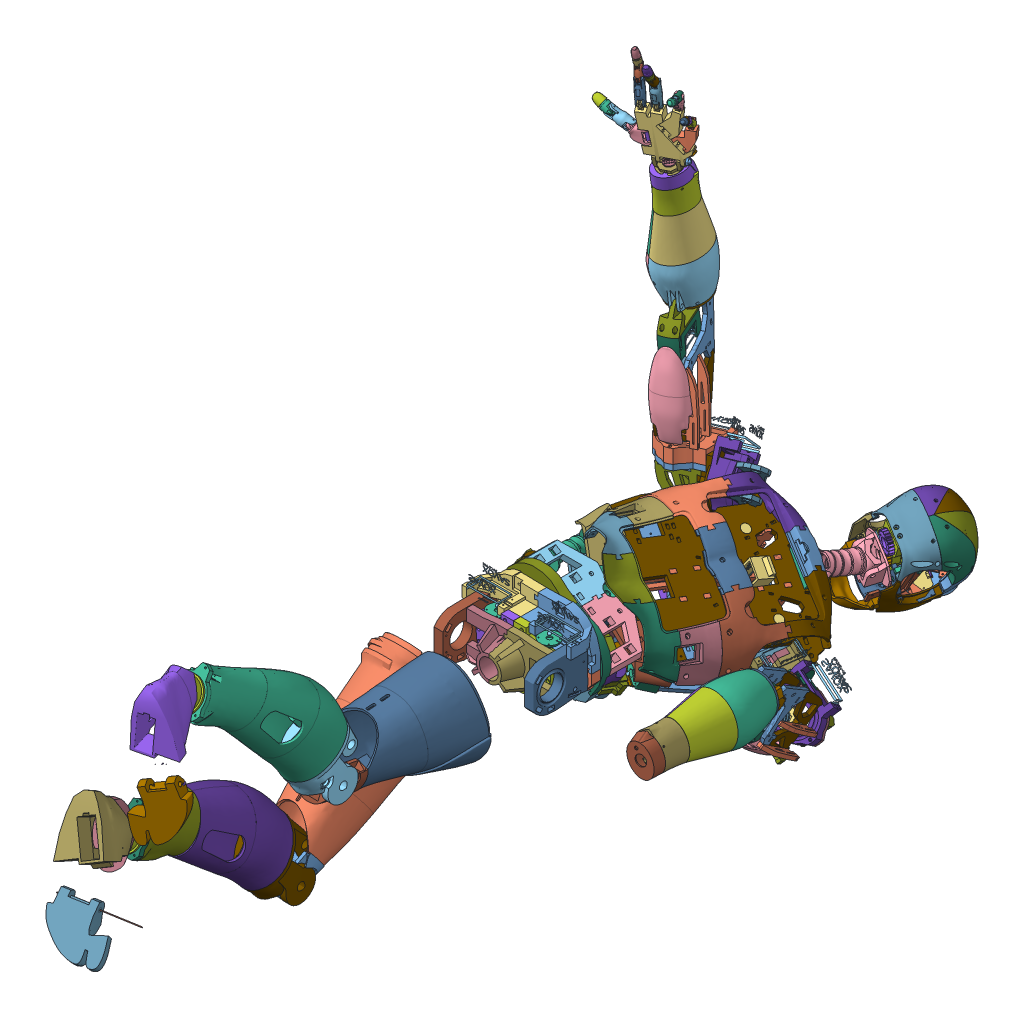
SolidWorks assembly inmoov, configuration 默认. Lengths in mm.
Overall size (1118.58 1250.99 1881.08).
271 component instances, 190 part files, 41 mates.
Components (placement in the parent):
- 盆骨-1: 盆骨 [默认] at (70.5927 39.7947 -15.7623) size (229.2 192.66 169.68)
  - 腹腔底10-1: 腹腔底10 [默认] at (-192.7214 -39.7004 -31.7756) size (122.01 95.66 63.55)
  - 腹腔底7-1: 腹腔底7 [默认] at (34.9288 -31.669 -31.7756) x (-1 0.000001 0) z (0 0.00001 1) size (144.05 113.37 90.99)
  - 腹腔底9-1: 腹腔底9 [默认] at (-192.7214 -39.7003 -31.7757) size (114.62 96.11 63.55)
  - 腹腔底8-1: 腹腔底8 [默认] at (34.9269 -31.6689 -31.7809) x (-1 -0.000002 0) z (0 0.000005 1) size (113.05 83.69 90.99)
  - 大舵机-1: 大舵机 [默认] at (-89.2868 14.2586 -3.7081) x (1 0 0) z (0 -0.000369 1) size (81.81 63.91 30.18)
  - 大舵机-3: 大舵机 [默认] at (-66.8639 10.2587 37.2872) x (-1 0 0) z (0 -0.000385 -1) size (81.81 63.91 30.18)
  - 腰部大螺栓-1: 腰部大螺栓 [默认] at (-193.5357 -116.8795 -27.4468) x (1 0 0) z (0 -0.000019 1) size (40.06 75.57 40.06)
  - 腰部大螺栓-2: 腰部大螺栓 [默认] at (-84.4909 -112.8794 -27.4312) x (1 0 0) z (0 -0.000013 1) size (40.06 75.57 40.06)
  - 盆骨1-1: 盆骨1 [默认] at (-156.4632 -100.0573 37.9672) x (0.00022 1 -0.000011) z (0 -0.000011 -1) size (127.7 105.68 15.11)
  - 盆骨2-1: 盆骨2 [默认] at (-156.2886 -100.4214 37.9672) x (-0.004429 0.99999 -0.000011) z (-0.000001 -0.000011 -1) size (127.7 78.47 15.11)
  - 腰部脊柱-1: 腰部脊柱 [默认] at (96.5025 -51.1472 22.3076) x (-0.920661 -0.390363 0.000004) z (0.000001 -0.000011 -1) size (94.05 93.78 91.39)
  - 盆腔右-1: 盆腔右 [默认] at (7.5496 -34.1365 36.3698) x (-0.003482 -0.003095 0.999989) z (0.999994 -0.000011 0.003482) size (127.1 98.38 18.86)
  - 盆腔大腿连接-1: 盆腔大腿连接 [默认] at (-164.2868 -34.1439 37.2078) x (-0.003562 0.003181 -0.999989) z (-0.999994 -0.000011 0.003562) size (127.1 98.38 18.86)
  - 盆骨4-1: 盆骨4 [默认] at (7.7497 18.3053 37.9656) x (-0.999967 -0.00818 0) z (0 0.000013 1) size (113.34 100.96 52.24)
  - 盆骨3-1: 盆骨3 [默认] at (8.5006 17.6463 37.9656) x (-1 -0.000493 0) z (0 0.000013 1) size (86.16 100.96 52.24)
- 腹腔底-1: 腹腔底 [默认] at (-4.5335 -58.4913 -79.9024) x (-0.842788 0.538245 -0.000007) z (0.000001 -0.000012 -1) size (236.98 173.63 160.06)
  - 腹腔底1-1: 腹腔底1 [默认] at (-115.9898 -31.5228 -86.4581) size (118.38 83.69 62.88)
  - 腹腔底3-1: 腹腔底3 [默认] at (-115.9897 -31.5228 -86.4581) x (1 0.000001 0) z (0 0 1) size (120.65 97.33 18.16)
  - 腹腔底4-1: 腹腔底4 [默认] at (-116.1614 -30.8776 -86.4608) x (0.999991 -0.004202 -0.000001) z (0.000001 0 1) size (144.03 121.61 18.16)
  - 腹腔底5-1: 腹腔底5 [默认] at (-115.9897 -31.5229 -86.458) x (1 0.000001 0) z (0 0.000001 1) size (61.43 24.96 50.27)
  - 腹腔底6-1: 腹腔底6 [默认] at (-116.1614 -30.8776 -86.4607) x (0.999991 -0.004202 -0.000001) z (0.000001 0 1) size (61.43 24.96 50.27)
  - 腹腔底2-1: 腹腔底2 [默认] at (-116.1614 -30.8774 -86.458) x (0.999991 -0.004202 -0.000001) z (0.000001 0 1) size (125.86 83.69 62.88)
  - 腰部脊柱2-1: 腰部脊柱2 [默认] at (-46.5918 207.4732 -86.4608) x (-0.004521 -0.99999 0) z (0 0 1) size (79.07 79.07 18.22)
  - 腹腔中前-1: 腹腔中前 [默认] at (-115.9166 -30.878 -86.4712) x (0.999991 -0.004202 -0.000001) z (0.000001 -0.000001 1) size (118.93 16.66 147.82)
  - 腹腔中背1-1: 腹腔中背1 [默认] at (-115.9899 -31.5227 -86.4302) x (1 0.000001 -0.000002) z (0.000002 -0.000001 1) size (113.55 25.26 111.94)
  - 腹腔中背2-1: 腹腔中背2 [默认] at (-116.1614 -30.8776 -86.4328) x (0.999991 -0.004202 -0.000001) z (0.000001 0 1) size (113.52 25.26 111.94)
  - 腹腔中-1: 腹腔中 [默认] at (-116.0394 -30.7589 -86.2911) x (0.999991 -0.004203 0) z (0 -0.000001 1) size (88.8 54.93 88.79)
  - 腹腔中2-1: 腹腔中2 [默认] at (-116.0669 -30.7588 -86.2536) x (0.999991 -0.004202 0) z (0 -0.000001 1) size (88.8 48.64 88.8)
  - 装饰-腹腔-1: 装饰-腹腔 [默认] at (-33.2725 -10.645 128.5221) x (0.000684 -0.000002 -1) z (-0.004202 -0.999991 -0.000001) size (73.69 73.49 13.68)
  - 装饰-腹腔-2: 装饰-腹腔 [默认] at (108.4671 -11.2406 -13.0249) x (-0.000684 0.000002 1) z (-0.004202 -0.999991 -0.000001) size (73.69 73.49 13.68)
  - 装饰-腹腔-3: 装饰-腹腔 [默认] at (108.3702 -11.2402 128.6191) x (-0.999991 0.004202 -0.000684) z (-0.004202 -0.999991 -0.000001) size (73.69 73.49 13.68)
  - 装饰-腹腔-4: 装饰-腹腔 [默认] at (-33.1756 -10.6453 -13.1219) x (0.999991 -0.004202 0.000684) z (-0.004202 -0.999991 -0.000001) size (73.69 73.49 13.68)
- 腹腔上-1: 腹腔上 [默认] at (48.5045 -53.3308 -158.6881) x (-0.793643 0.502129 -0.343506) z (0.290273 -0.18368 -0.93915) size (307.58 77.32 113.84)
  - 腹腔前1-1: 腹腔前1 [默认] at (-79.3802 -63.8968 -192.1693) size (103 23.38 76.42)
  - 腹腔后1-1: 腹腔后1 [默认] at (227.4254 159.402 -192.6182) x (-0.999998 -0.000036 0.002224) z (0.002224 -0.000001 0.999998) size (96.82 10.08 80.86)
  - 腹腔后2-1: 腹腔后2 [默认] at (-79.8769 -63.9893 -191.9254) x (0.999997 0.000073 -0.002314) z (0.002314 -0.000001 0.999997) size (112.71 23.37 76.42)
  - 腹腔后3-1: 腹腔后3 [默认] at (-80.266 -63.9781 -191.4841) x (0.99999 0 -0.004449) z (0.004449 -0.000001 0.99999) size (112.71 23.37 76.42)
  - 腹腔后1-2: 腹腔后1 [默认] at (-79.8184 -130.9308 -191.935) x (0.999998 0.000036 -0.002225) z (0.002225 0 0.999998) size (96.82 10.08 80.86)
  - 腹腔中3-1: 腹腔中3 [默认] at (-80.0009 -63.5291 -193.4037) x (0.999965 -0.004935 0.006744) z (-0.006745 -0.000033 0.999977) size (86.15 66.75 71.31)
  - 腹腔前2-1: 腹腔前2 [默认] at (-79.759 -63.9636 -191.9533) x (0.999998 0.000073 -0.002134) z (0.002134 0 0.999998) size (103 23.38 76.42)
  - 腰肌螺母-1: 腰肌螺母 [默认] at (171.7646 -14.2155 -47.3665) x (0.997648 0.000036 0.068548) z (-0.068548 -0.000004 0.997648) size (50.56 57 34.3)
  - 腰肌螺母-3: 腰肌螺母 [默认] at (-19.0221 42.7776 -45.2497) x (-0.999985 -0.000036 -0.005434) z (-0.005434 -0.000002 0.999985) size (50.56 57 34.3)
- 腰部-1: 腰部 [默认] at (43.4407 -39.2735 -108.6148) x (-0.7938 0.506957 -0.335971) z (0.283148 -0.180841 -0.941872) size (88.76 53.21 141.98)
  - 腰部舵机安装盒-1: 腰部舵机安装盒 [默认] at (-60.724 -20.5722 -23.2224) size (87.93 52.56 34.36)
  - 大舵机-1: 大舵机 [默认] at (-100.7443 -15.1822 39.809) x (1 0 -0.000002) z (0 1 0.000383) size (81.81 63.91 30.18)
  - 舵机盘-1: 舵机盘 [默认] at (-61.0228 -14.6756 36.5262) x (0.992401 0.000027 -0.123044) z (0.123044 -0.000435 0.992401) size (40.31 40 12.26)
  - 腰部大螺栓-1: 腰部大螺栓 [默认] at (-108.8185 -9.5775 169.4468) x (0.909531 -0.415637 -0.000003) z (0.415637 0.909531 0.000025) size (40.06 75.57 40.06)
- 腰部-2: 腰部 [默认] at (-62.5662 40.207 -95.5581) x (0.844485 -0.53435 0.036267) z (0.030644 -0.019398 -0.999342) size (88.76 53.21 141.98)
  - 腰部舵机安装盒-1: 腰部舵机安装盒 [默认] at (-60.724 -20.5722 -23.2224) size (87.93 52.56 34.36)
  - 大舵机-1: 大舵机 [默认] at (-100.7443 -15.1822 39.809) x (1 0 -0.000002) z (0 1 0.000383) size (81.81 63.91 30.18)
  - 舵机盘-1: 舵机盘 [默认] at (-61.0228 -14.6756 36.5262) x (0.992401 0.000027 -0.123044) z (0.123044 -0.000435 0.992401) size (40.31 40 12.26)
  - 腰部大螺栓-1: 腰部大螺栓 [默认] at (-108.8185 -9.5775 169.4468) x (0.909531 -0.415637 -0.000003) z (0.415637 0.909531 0.000025) size (40.06 75.57 40.06)
- 身子板-1: 身子板 [默认] at (-659.1415 377.3457 523.4472) x (-0.069913 0.797457 -0.599312) z (-0.784162 -0.415288 -0.461114) size (516.48 525.32 527.33)
  - 后背板-1: 后背板 [默认] at (143.3492 1191.9158 -17.9372) x (-0.6608 0.486586 -0.57147) z (0.636508 -0.040187 -0.770222) size (310.71 330.4 10)
  - 胸前板-1: 胸前板 [默认] at (61.9607 1209.7037 0.4805) x (-0.6608 0.486586 -0.57147) z (0.636508 -0.040187 -0.770222) size (310.06 296.42 10)
  - 脊柱1-1: 脊柱1 [默认] at (34.0384 1054.7167 -14.5078) x (0.6608 -0.486586 0.57147) z (0.397745 0.872708 0.28316) size (54.6 76.71 282.55)
  - 脊柱1-2: 脊柱1 [默认] at (65.4264 1031.6039 12.6371) x (0.6608 -0.486586 0.57147) z (0.397745 0.872708 0.28316) size (54.6 76.71 282.55)
  - 胸肌3-1: 胸肌3 [默认] at (252.0953 1308.157 52.803) x (0.61608 -0.574219 0.539183) z (-0.463673 -0.81773 -0.341066) size (37.4 76.95 25.87)
  - 胸肌3-2: 胸肌3 [默认] at (117.556 1377.4336 -61.9943) x (0.749033 -0.205605 0.629822) z (-0.1834 -0.977826 -0.101096) size (37.4 76.95 25.87)
  - 装饰-腹腔-上-1: 装饰-腹腔-上 [默认] at (-153.4195 944.3871 -111.8547) x (0.661803 -0.484378 0.572185) z (0.396073 0.873935 0.281715) size (98.85 49.72 33.76)
  - 装饰-腹腔-上2-1: 装饰-腹腔-上2 [默认] at (85.1244 1050.2994 15.2678) x (0.660957 -0.486242 0.571581) z (-0.397485 -0.8729 -0.282935) size (98.85 49.72 33.76)
  - 装饰-胸腔1-1: 装饰-胸腔1 [默认] at (-74.1529 1143.352 -37.1333) x (0.6608 -0.486586 0.57147) z (0.397745 0.872708 0.28316) size (109.48 65.08 34.36)
  - 装饰-胸腔2-1: 装饰-胸腔2 [默认] at (-74.6569 1143.2216 -36.3801) x (0.6608 -0.486586 0.57147) z (0.397745 0.872708 0.28316) size (69.28 69.05 67.19)
  - 装饰-胸腔3-1: 装饰-胸腔3 [默认] at (-74.46 1143.7266 -36.7278) x (0.6608 -0.486586 0.57147) z (0.397745 0.872708 0.28316) size (109.15 65.08 34.37)
  - 装饰-胸腔4-1: 装饰-胸腔4 [默认] at (-74.0615 1142.7469 -36.9122) x (0.660896 -0.486866 0.57112) z (0.397947 0.872559 0.283335) size (119.01 63.05 121.18)
  - 装饰-胸腔5-1: 装饰-胸腔5 [默认] at (-74.3693 1142.9367 -36.8164) x (0.660864 -0.485825 0.572042) z (0.397182 0.873122 0.282673) size (119.01 63.06 121.15)
  - 装饰-胸腔6-1: 装饰-胸腔6 [默认] at (44.1853 1289.4703 15.9146) x (0.661053 -0.486028 0.571651) z (0.397323 0.873019 0.282795) size (117.32 26.45 49.76)
  - 装饰-胸腔7-1: 装饰-胸腔7 [默认] at (44.3553 1289.8426 16.0358) x (0.659604 -0.489202 0.570618) z (0.399726 0.871244 0.284874) size (117.42 26.45 49.76)
  - 装饰-胸腔-搞什么啊这个也要分开两个明明一个就可以-1: 装饰-胸腔-搞什么啊这个也要分开两个明明一个就可以 [默认] at (37.1283 1215.9714 45.2793) x (0.6608 -0.486586 0.57147) z (0.397745 0.872708 0.28316) size (138.82 53.92 70.62)
  - 装饰-腹腔-上3-1: 装饰-腹腔-上3 [默认] at (-52.0677 1129.5819 -35.7586) x (0.6608 -0.486586 0.57147) z (0.397745 0.872708 0.28316) size (131.99 51.42 32.36)
  - 装饰-腹腔-上4-1: 装饰-腹腔-上4 [默认] at (-51.2643 1128.8117 -35.0374) x (0.6608 -0.486586 0.57147) z (0.397745 0.872708 0.28316) size (131.99 51.42 32.36)
  - 装饰-背部-1: 装饰-背部 [默认] at (556.6771 1211.3347 228.4405) x (0.653769 -0.401724 0.641252) z (0.325737 -0.615491 -0.717681) size (351.18 364.48 345.06)
    - 装饰-背部2-1: 装饰-背部2 [默认] at (-578.9545 274.381 92.1313) x (0.989065 0.068101 0.130814) z (0.134185 -0.783586 -0.606619) size (111.18 27.71 50.53)
    - 装饰-背部3-1: 装饰-背部3 [默认] at (-579.0285 274.2163 91.9579) x (0.988774 0.069516 0.132264) z (0.13619 -0.783443 -0.606358) size (118.1 95.29 111.5)
    - 装饰-背部4-1: 装饰-背部4 [默认] at (-583.8515 325.981 132.3484) x (0.988455 0.07552 0.131351) z (0.140337 -0.783133 -0.605812) size (70.93 77.01 90.21)
    - 装饰-背部5-1: 装饰-背部5 [默认] at (-581.9356 326.1989 132.2577) x (0.98844 0.071421 0.133738) z (0.138594 -0.783263 -0.606045) size (70.91 77.12 90.21)
    - 装饰-背部6-1: 装饰-背部6 [默认] at (-573.266 248.1563 194.7745) x (0.988455 0.075515 0.131352) z (-0.140333 0.783133 0.605813) size (111.34 97.12 112.81)
    - 装饰-背部7-1: 装饰-背部7 [默认] at (-571.5995 248.3153 194.9496) x (0.988701 0.074142 0.13028) z (-0.138594 0.783263 0.606045) size (111.34 97.12 112.81)
    - 装饰-背部8-2: 装饰-背部8 [默认] at (-571.9454 247.7082 194.4628) x (0.987776 0.079245 0.134236) z (-0.14504 0.782763 0.605182) size (84.93 29.99 71.45)
    - 装饰-背部-上-1: 装饰-背部-上 [默认] at (-541.2593 199.9763 28.2233) x (0.988704 0.06993 0.132565) z (0.136627 -0.784148 -0.605347) size (112.37 87.9 117.46)
    - 装饰-背部-上2-1: 装饰-背部-上2 [默认] at (-541.292 199.909 28.179) x (0.988658 0.070179 0.132776) z (0.136952 -0.784125 -0.605303) size (112.42 86.19 116.36)
    - 装饰-背部-上3-2: 装饰-背部-上3 [默认] at (-541.6661 199.5094 29.6724) x (0.98915 0.071334 0.128425) z (0.135493 -0.780835 -0.609868) size (76.75 23.59 35.23)
    - 装饰-背部9-1: 装饰-背部9 [默认] at (-578.8974 274.377 92.0652) x (0.989048 0.067927 0.131035) z (0.134185 -0.783586 -0.606619) size (118.1 95.29 111.5)
- 颈部舵机包裹盒-1: 颈部舵机包裹盒 [默认] at (66.463 -67.2427 -357.0875) x (-0.794313 0.502684 -0.341139) z (0.227875 -0.274003 -0.934342) size (53.5 87.93 30.73)
- 大舵机-1: 大舵机 [默认] at (21.2826 -92.8743 -428.0501) x (0.563153 0.819896 -0.103099) z (0.794399 -0.502788 0.340784) size (81.81 63.91 30.18)
- 颈椎-1: 颈椎 [默认] at (327.5718 -830.9296 572.5602) x (-0.806641 0.510346 -0.298123) z (0.259011 -0.148159 -0.954443) size (60.66 53.48 115.35)
- 颈部连接-1: 颈部连接 [默认] at (100.7339 -79.9016 -435.0873) x (-0.794355 0.502623 -0.34113) z (0.288264 -0.182411 -0.940016) size (54.59 64.81 34.68)
- 颈部连接2-1: 颈部连接2 [默认] at (100.5898 -79.8584 -435.1883) x (-0.7943 0.502587 -0.341312) z (0.288418 -0.182507 -0.93995) size (69.42 17.54 31.49)
- 头-1: 头 [默认] at (159.0523 55.7112 -671.473) x (-0.81491 0.49549 -0.300686) z (0.388055 0.081094 -0.918062) size (147.84 221.42 240.31)
  - 支架-2: 支架 [默认] at (-124.447 -159.0127 -70.7992) size (53.91 91.64 57.56)
  - 颈椎齿轮1-2: 颈椎齿轮1 [默认] at (-81.2129 -98.5858 -79.9856) size (42.66 42.67 32.83)
  - 颈椎齿轮2-2: 颈椎齿轮2 [默认] at (-82.3614 -57.8278 -79.9768) x (0.087374 -0.996176 0) z (0 0 1) size (42.66 42.66 44.97)
  - 脸部右支架-2: 脸部右支架 [默认] at (-124.6512 -158.9164 -70.9912) x (0.999993 -0.00385 0) z (0 0 1) size (50.18 81.65 18.67)
  - 下颚右支架-2: 下颚右支架 [默认] at (-105.7528 -137.0128 -114.8083) x (0.999987 -0.003839 0.003287) z (-0.003661 -0.101881 0.99479) size (8.26 106.97 83.58)
  - 大舵机-1: 大舵机 [默认] at (-79.6637 -141.6142 -32.115) x (0 0.999997 0.002621) z (0.999996 -0.000007 0.002719) size (81.81 63.91 30.18)
  - 舵机支架-2: 舵机支架 [默认] at (-124.9768 -158.8555 -71.2485) x (0.999995 -0.000008 0.003099) z (-0.003099 -0.002621 0.999992) size (64.63 107.35 76.67)
  - 迷你舵机-2: 迷你舵机 [默认] at (-48.2513 -135.944 28.1702) x (-0.999986 -0.004998 0.001659) z (-0.000305 -0.259577 -0.965722) size (32.82 12.3 30.6)
  - 后脑勺-2: 后脑勺 [默认] at (-472.2134 -287.0548 -1807.4761) x (0.999892 0.014512 -0.002292) z (0.001793 0.034306 0.99941) size (136.35 70.29 65.6)
  - 后脑右-2: 后脑右 [默认] at (-134.4625 -95.0757 -21.5694) x (0.99996 0.004746 -0.007645) z (0.007474 0.03506 0.999357) size (72.75 112.74 72.41)
  - 后脑右上-2: 后脑右上 [默认] at (-470.5392 -285.4493 -1807.7537) x (0.999944 0.010512 -0.000771) z (0.000404 0.034862 0.999392) size (54.09 115.71 76.28)
  - 后脑左-2: 后脑左 [默认] at (-133.0899 -96.0354 -22.0012) x (0.999891 0.014487 -0.002996) z (0.002487 0.035016 0.999384) size (72.75 112.69 72.41)
  - 后脑左上-2: 后脑左上 [默认] at (-485.3133 -292.4826 -1803.1863) x (0.999906 0.010204 -0.009158) z (0.008757 0.038668 0.999214) size (66.14 115.71 76.29)
  - 前额右-1: 前额右 [默认] at (-485.0704 -271.1759 -1806.139) x (0.999871 0.013496 -0.008737) z (0.008381 0.026215 0.999621) size (72.11 94.93 64.78)
  - 前额右上-1: 前额右上 [默认] at (-457.4772 -289.9568 -1810.8211) x (0.999517 0.030818 0.004033) z (-0.005025 0.03218 0.999469) size (85.15 107.55 75.34)
  - 前额左-1: 前额左 [默认] at (-473.2004 -218.3333 -1813.179) x (0.999982 0.005763 -0.001907) z (0.001915 -0.001235 0.999997) size (91.46 102.46 64.78)
  - 前额左上-1: 前额左上 [默认] at (-467.29 -207.0531 -1815.3492) x (0.999805 -0.019571 0.002504) z (-0.002528 -0.001167 0.999996) size (80.92 107.55 80.15)
  - 脸部支架-1: 脸部支架 [默认] at (-124.4772 -159.0849 -70.9912) x (1 0 0) z (0 0 1) size (50.3 81.55 19.17)
  - 下颚传动右-1: 下颚传动右 [默认] at (-124.473 -158.7731 -70.8425) x (0.999987 -0.003839 0.003287) z (-0.003274 0.003227 0.999989) size (17.04 36.62 42.69)
  - 下颚传动左-1: 下颚传动左 [默认] at (-124.6359 -159.1135 -69.5647) x (0.999554 0.000509 -0.029855) z (0.02986 -0.017025 0.999409) size (17.04 36.62 42.69)
  - 下颚支架2-1: 下颚支架2 [默认] at (-110.2934 -133.1949 -115.5804) x (0.999554 0.000509 -0.029855) z (0.029561 -0.157888 0.987015) size (8.26 106.97 83.58)
  - 下颚-1: 下颚 [默认] at (-522.7989 64.0778 -1802.2262) x (0.999625 0.002745 -0.027234) z (0.027326 -0.157888 0.987079) size (113.02 62.78 57.99)
  - 上颚-1: 上颚 [默认] at (-472.0966 -231.4046 -1812.4343) x (0.999982 0.005763 -0.001859) z (0.001823 0.006208 0.999979) size (141.83 76.87 99.46)
  - 脸-1: 脸 [默认] at (-124.4869 -198.7826 -68.0514) x (0.999982 0.005763 -0.001864) z (0.00182 0.007618 0.999969) size (130.55 56.05 65.23)
  - 耳朵-1: 耳朵 [默认] at (-134.5341 -125.1811 -74.3435) x (0.999786 -0.009234 0.01852) z (-0.01668 0.170193 0.98527) size (16.1 91.01 91.01)
  - 耳根-1: 耳根 [默认] at (49.6286 -51.4238 -103.8814) x (0.999982 0.005763 -0.001864) z (0.00182 0.007618 0.999969) size (22.04 103.89 112.83)
  - 眼睛支架-1: 眼睛支架 [默认] at (-108.8481 -200.0988 -91.2528) x (0.999986 0.005204 -0.000894) z (-0.000487 0.259573 0.965723) size (65.05 33.31 75.11)
  - 眼球-1: 眼球 [默认] at (-37.7048 -168.4489 -19.8199) x (0.742559 0.129649 -0.657113) z (0.55836 0.422027 0.714232) size (36.68 12.46 36.68)
  - 眼球板-1: 眼球板 [默认] at (-41.6405 -162.3342 -45.3078) x (0.929364 0.356416 -0.096182) z (0.000385 0.259603 0.965715) size (33.8 15.18 44.6)
  - 眼球板附加-1: 眼球板附加 [默认] at (-90.8952 -224.7754 -84.1839) x (0.929364 0.356438 -0.0961) z (0.000313 0.259557 0.965728) size (30.53 13.48 33.7)
  - 眼球左右传动板-1: 眼球左右传动板 [默认] at (-13.1585 -143.7871 100.851) x (-0.997305 -0.070778 0.019339) z (-0.000305 -0.259576 -0.965723) size (35.43 8.85 2.99)
  - 迷你舵机-3: 迷你舵机 [默认] at (-37.698 -157.934 -40.8747) x (-0.006048 0.965705 -0.259571) z (-0.999982 -0.005762 0.001864) size (32.82 12.3 30.6)
  - 下颚螺母连接块-1: 下颚螺母连接块 [默认] at (-102.7393 -60.0107 -39.1407) x (0.999554 0.000509 -0.029855) z (0.029271 0.180858 0.983074) size (86.95 16.37 12.1)
  - 右耳根-1: 右耳根 [默认] at (-134.1706 -208.8052 -146.4024) x (0.999982 0.005763 -0.001864) z (0.00182 0.007618 0.999969) size (17.42 103.79 112.96)
  - 鼻骨-1: 鼻骨 [默认] at (-124.5584 -198.8505 -68.1492) x (0.999982 0.005763 -0.001864) z (0.00182 0.007616 0.999969) size (21 31.57 49.5)
  - 耳朵-2: 耳朵 [默认] at (10.2094 -58.2202 -97.4824) x (-0.999622 -0.016404 0.022043) z (0.013501 0.405482 0.914003) size (16.1 91.01 91.01)
  - 眼球板-右-1: 眼球板-右 [默认] at (-104.0961 -165.6703 -44.3805) x (0.9254 0.365928 -0.098651) z (0.000306 0.259576 0.965723) size (33.8 15.22 44.6)
  - 眼球板附加-右-1: 眼球板附加-右 [默认] at (-94.3263 -205.4862 -89.3547) x (0.9254 0.365928 -0.09865) z (0.000313 0.259557 0.965728) size (30.53 13.48 33.7)
  - 眼球-2: 眼球 [默认] at (-93.486 -163.662 0.7412) x (-0.309518 -0.367105 -0.877173) z (0.872458 0.257233 -0.415509) size (36.68 12.46 36.68)
  - 眼球左右传动板-2: 眼球左右传动板 [默认] at (-121.0355 -192.8146 -92.7775) x (0.99458 -0.100492 0.026697) z (0.000305 0.259577 0.965722) size (35.43 8.85 2.99)
- 颈椎上-1: 颈椎上 [默认] at (-279.4452 -552.5793 1065.328) x (-0.806305 0.512366 -0.295558) z (0.388055 0.081094 -0.918062) size (92.29 80.59 33.71)
- 颈部肌肉螺栓-1: 颈部肌肉螺栓 [默认] at (39.8383 -63.0159 -361.6888) x (-0.193286 0.927762 -0.319216) z (0.227872 -0.274007 -0.934342) size (39.72 39.72 100.52)
- 颈部肌肉-1: 颈部肌肉 [默认] at (45.7079 -68.3009 -373.5197) x (-0.274536 0.902575 -0.331646) z (0.227871 -0.274007 -0.934342) size (28.08 28.58 122.79)
- 右脚-1: 右脚 [默认] at (-9.6404 -547.6759 575.1252) x (-0.687566 -0.511254 -0.515629) z (0.723091 -0.546902 -0.421945) size (820.43 699.67 726.99)
  - 右小腿-1: 右小腿 [默认] at (-400.1104 -176.0875 -338.5039) x (0.826596 -0.548948 -0.124075) z (-0.193597 -0.484354 0.853183) size (371.31 442.39 332.73)
    - 膝盖右下-1: 膝盖右下 [默认] at (-523.7529 501.294 -106.0649) x (0.676216 -0.047439 -0.735174) z (0.529558 0.725052 0.440304) size (103.93 135.07 96.53)
    - 右小腿-1: 右小腿 [默认] at (-1509.5207 407.2534 356.5703) x (0.676217 -0.047438 -0.735174) z (0.427539 0.837953 0.339183) size (125.4 159.22 355.37)
  - 脚踝-1: 脚踝 [默认] at (-626.971 399.431 -514.5499) x (-0.479837 0.817786 0.317778) z (-0.730035 -0.171261 -0.661602) size (66.72 66.73 45.96)
  - 右脚-1: 右脚 [默认] at (-1815.1824 1208.5317 561.4844) x (0.460628 -0.248169 -0.852194) z (0.711788 0.676872 0.187623) size (110.05 224.47 118.54)
  - 右脚趾-1: 右脚趾 [默认] at (316.2614 -486.3972 -1339.3575) x (-0.465224 0.252235 0.848495) z (0.70204 0.688985 0.180107) size (97.91 137.78 40.59)
  - 大腿右-1: 大腿右 [默认] at (-23.3857 -51.9681 0) size (470.68 508.98 446.5)
    - 大腿右侧-已翻转-1: 大腿右侧-已翻转 [默认] at (246.4325 -358.6742 385.4816) x (0.689353 -0.063677 -0.721621) z (0.569669 0.66301 0.485691) size (162.86 209.38 464.67)
    - 膝盖右上-1: 膝盖右上 [默认] at (-108.0099 340.3112 -728.0834) x (0.676216 -0.047439 -0.735174) z (-0.50532 -0.756033 -0.416011) size (109 86.01 77.55)
- 右手-1: 右手 [默认] at (-303.0662 524.5668 645.1342) x (0.944725 -0.121151 0.304657) z (0.242681 0.883202 -0.401322) size (537.65 583.01 323.75)
  - 右肩内-1: 右肩内 [默认] at (-554.4913 207.3714 -41.3596) x (-0.259119 0.270063 0.927321) z (-0.767636 0.525104 -0.367424) size (165.73 145.33 179.96)
    - 右手11-1: 右手11 [默认] at (-66.7029 2791.7652 -1676.8682) x (0.419842 -0.819664 0.389722) z (0.645927 0.571499 0.50613) size (37.79 102.6 113.4)
    - 右手2-1: 右手2 [默认] at (148.1443 1489.8573 -466.1757) x (0.419847 -0.819659 0.389727) z (0.644936 0.571566 0.507316) size (15.58 90.74 103.51)
    - 肩胛骨-1: 肩胛骨 [默认] at (64.3449 1261.6061 -25.7326) x (-0.419847 0.819659 -0.389727) z (-0.638581 0.038354 0.768598) size (53.97 102.32 7.5)
    - 肩胛骨-2: 肩胛骨 [默认] at (93.0578 1259.8856 -60.283) x (-0.419847 0.819659 -0.389727) z (-0.638581 0.038354 0.768598) size (53.97 102.32 7.5)
    - 大舵机-1: 大舵机 [默认] at (37.9422 1228.7537 -119.7914) x (0.645835 0.571505 0.506241) z (-0.420179 0.819685 -0.389315) size (81.81 63.91 30.18)
  - 右肩-1: 右肩 [默认] at origin size (162.66 157.92 218.84)
    - 右手肩部肩胛传动-1: 右手肩部肩胛传动 [默认] at (1087.3872 2772.2295 3074.4342) x (-0.888426 -0.343703 0.30425) z (-0.433363 0.846544 -0.309127) size (30.18 101.64 100.56)
    - 肩部直角件-1: 肩部直角件 [默认] at (282.9051 1259.6079 -33.3815) x (0.88669 0.346881 -0.305702) z (-0.436818 0.8452 -0.30794) size (77.13 53.27 74.94)
    - 肩部直角件-2: 肩部直角件 [默认] at (276.0584 1241.2276 -74.0957) x (0.88669 0.346881 -0.305702) z (-0.436818 0.8452 -0.30794) size (77.13 53.27 74.94)
    - 右手2-1: 右手2 [默认] at (452.6345 1141.8665 366.7625) x (-0.437587 0.844899 -0.307674) z (0.886311 0.347615 -0.305969) size (15.58 90.74 103.51)
    - 右手4-1: 右手4 [默认] at (2509.158 5052.0987 7340.4223) x (-0.88622 -0.347387 0.30649) z (-0.437571 0.844956 -0.307539) size (110.5 102.59 37.78)
    - 大舵机-1: 大舵机 [默认] at (234.6575 1242.8525 -4.5609) x (0.88622 0.347387 -0.30649) z (0.437514 -0.84511 0.307197) size (81.81 63.91 30.18)
  - 手大臂-1: 手大臂 [默认] at (281.4226 98.1435 194.7173) x (0.5894 0.372248 0.716965) z (-0.807537 0.295872 0.510239) size (168.57 259.68 213.5)
    - 肩部大臂传动-1: 肩部大臂传动 [默认] at (387.2336 923.2205 71.7955) x (-0.731537 0.195249 -0.653246) z (-0.163767 0.879749 0.446343) size (92.57 93.45 30.17)
    - 左肩7-1: 左肩7 [默认] at (272.9463 951.3318 1.1554) x (0.745885 -0.299351 0.595017) z (-0.661867 -0.433357 0.611665) size (120.84 98.18 7.5)
    - 左肩7-2: 左肩7 [默认] at (242.8694 931.6386 28.9516) x (0.745885 -0.299351 0.595017) z (-0.661867 -0.433357 0.611665) size (120.84 98.18 7.5)
    - 左肩8-1: 左肩8 [默认] at (243.1543 931.2846 29.009) x (0.745697 -0.297235 0.596312) z (-0.661867 -0.433357 0.611665) size (117.33 120.91 7.5)
    - 左肩8-2: 左肩8 [默认] at (273.2313 950.9777 1.2129) x (0.745697 -0.297235 0.596312) z (-0.661867 -0.433357 0.611665) size (117.33 120.91 7.5)
    - 左手1-1: 左手1 [默认] at (376.8563 964.0188 -11.4035) x (-0.661867 -0.433359 0.611664) z (-0.154337 0.87726 0.454527) size (26.4 52.78 131.72)
    - 左手1-2: 左手1 [默认] at (239.2225 868.3069 126.4972) x (0.661867 0.433355 -0.611666) z (-0.1551 0.877477 0.453849) size (26.4 52.78 131.72)
    - 二头肌3-1: 二头肌3 [默认] at (204.2298 1244.5751 220.1542) x (0.662738 0.432715 -0.611175) z (0.095007 -0.858141 -0.504547) size (52.98 38.41 29.61)
    - 装饰-手-1: 装饰-手 [默认] at (273.6933 1134.3266 115.4714) x (-0.661867 -0.433357 0.611665) z (0.164084 -0.879931 -0.445868) size (72.28 34.51 167.42)
  - 右手小臂-1: 右手小臂 [默认] at (460.3119 1000.0381 4.7231) x (-0.891849 -0.449213 0.053033) z (0.413408 -0.857063 -0.30747) size (104.14 106.75 306.73)
    - 手小臂4-1: 手小臂4 [默认] at (-35.3772 -52.064 -52.8214) size (92.61 92.23 105.64)
    - 手小臂1-1: 手小臂1 [默认] at (-46.9087 -66.5848 -52.8216) x (1 -0.000001 0.000002) z (-0.000002 -0.000002 1) size (95.98 93.78 105.56)
    - 手小臂2-1: 手小臂2 [默认] at (-46.9299 -66.5664 -52.8214) x (1 0 0) z (0 0 1) size (89.17 83.71 97.5)
    - 手小臂3-1: 手小臂3 [默认] at (-35.3833 -52.0586 -52.8214) x (1 0 0) z (0 0 1) size (87.69 81.42 97.5)
    - 左手肘部1-1: 左手肘部1 [默认] at (-69.0451 -74.9778 -84.1655) x (0.99999 0.004388 0.000046) z (-0.000047 0.000041 1) size (53.68 52.66 26.01)
    - 左手肘部2-1: 左手肘部2 [默认] at (-69.0287 -74.8624 -84.1647) x (0.99999 0.004388 0) z (0 0 1) size (81.43 78.13 16.17)
    - 手小臂5-1: 手小臂5 [默认] at (-68.5152 -75.0354 -84.169) x (0.999934 0.011528 0.000006) z (-0.000006 0.000009 1) size (63.74 62.99 37.95)
    - 手小臂6-1: 手小臂6 [默认] at (-68.676 -74.9885 -84.1646) x (0.999954 0.009584 0) z (0 0 1) size (68.76 67.89 54.52)
  - 胸肌-1: 胸肌 [默认] at (-350.7412 174.3378 -447.1855) x (-0.837933 0.530294 -0.129063) z (0.299505 0.249104 -0.921002) size (155.76 171.86 100.85)
    - 胸肌-1: 胸肌 [默认] at (42.5811 1189.4374 -14.3845) x (-0.721053 0.229657 0.653713) z (0.364762 0.927967 0.076331) size (87.93 53.5 40.57)
    - 大舵机-1: 大舵机 [默认] at (105.8942 1225.7471 -26.2767) x (-0.670456 0.342557 0.658136) z (0.589263 -0.293155 0.752881) size (81.81 63.91 30.18)
    - 胸肌2-1: 胸肌2 [默认] at (80.0196 1232.837 63.9463) x (0.256759 -0.272851 -0.927161) z (0.486716 0.865298 -0.11986) size (44.82 39.55 103.35)
  - 二头肌-1: 二头肌 [默认] at (435.1759 1104.5476 -0.7721) x (0.892491 0.447603 -0.055779) z (-0.450917 0.882185 -0.135736) size (64.66 92.03 212.69)
    - 二头肌2-1: 二头肌2 [默认] at (-46.5387 -31.4799 -64.4877) size (35.76 91.86 42.9)
    - 二头肌-1: 二头肌 [默认] at (-46.5652 -31.142 -64.5044) x (1 0 0.000001) z (-0.000001 -0.000213 1) size (35.73 87.01 43.05)
    - 大舵机-1: 大舵机 [默认] at (-49.4032 97.0264 44.0826) x (0 -1 0) z (1 0 0.00038) size (81.81 63.91 30.18)
    - 胸肌2-1: 胸肌2 [默认] at (-58.8082 17.4553 38.2859) x (0.966623 -0.224721 -0.123042) z (0.119747 -0.028286 0.992401) size (44.82 39.55 103.35)
- 左手-1: 左手 [默认] at (539.8861 1082.4743 -69.5288) x (0.590038 0.026416 -0.806943) z (-0.698016 0.518968 -0.493402) size (356.76 610.28 530.73)
  - 左肩Y-1: 左肩Y [默认] at (-425.3665 38.1672 215.8927) x (0.944082 -0.170609 0.282137) z (-0.244635 0.211231 0.946327) size (147.57 149.81 161.52)
    - 左肩1-1: 左肩1 [默认] at (81.8496 1233.3041 -28.556) x (-0.693278 0.059711 0.718192) z (0.257595 0.951257 0.169572) size (42.36 102.6 113.4)
    - 肩胛骨-1: 肩胛骨 [默认] at (152.2512 1256.0021 7.2252) x (-0.693278 0.05971 0.718192) z (0.673061 -0.302563 0.674867) size (53.97 102.32 7.5)
    - 肩胛骨-2: 肩胛骨 [默认] at (121.9648 1269.6109 -23.142) x (-0.693278 0.05971 0.718192) z (0.673061 -0.302563 0.674867) size (53.97 102.32 7.5)
    - 大舵机-1: 大舵机 [默认] at (100.973 1174.5117 50.5653) x (0.257494 0.951303 0.16947) z (0.693122 -0.059641 -0.718348) size (81.81 63.91 30.18)
  - 左肩X1-1: 左肩X1 [默认] at (638.5227 216.3713 354.0647) x (-0.9289 -0.339263 0.148477) z (-0.018323 -0.358338 -0.933412) size (179.39 149.77 193.77)
    - 左肩2-1: 左肩2 [默认] at (268.5393 1179.8685 -71.3561) x (0.71804 0.432088 -0.545636) z (-0.3066 0.900162 0.309361) size (30.18 101.64 100.56)
    - 肩部直角件-1: 肩部直角件 [默认] at (290.825 1243.3511 -109.5882) x (0.717017 0.435573 -0.544208) z (-0.309394 0.898474 0.311481) size (77.13 53.27 74.94)
    - 肩部直角件-2: 肩部直角件 [默认] at (262.4446 1245.8556 -144.9767) x (0.717017 0.435573 -0.544208) z (-0.309394 0.898474 0.311481) size (77.13 53.27 74.94)
    - 左肩4-1: 左肩4 [默认] at (306.3128 1182.6315 -101.0566) x (0.716123 0.43816 -0.543308) z (-0.31155 0.897223 0.312932) size (103.51 90.73 21.16)
    - 左肩5-1: 左肩5 [默认] at (306.4347 1182.7123 -101.1669) x (0.716671 0.438111 -0.542624) z (-0.31155 0.897223 0.312932) size (110.5 102.59 37.78)
    - 大舵机-1: 大舵机 [默认] at (220.1364 1190.0041 -139.2815) x (0.716671 0.438111 -0.542624) z (-0.311313 0.897202 0.313228) size (81.81 63.91 30.18)
  - 手大臂-1: 手大臂 [默认] at (-589.6889 571.1769 978.1454) x (0.950524 0.090035 0.297319) z (-0.210052 0.891402 0.401597) size (168.57 259.68 213.5)
    - 肩部大臂传动-1: 肩部大臂传动 [默认] at (387.2336 923.2205 71.7955) x (-0.731537 0.195249 -0.653246) z (-0.163767 0.879749 0.446343) size (92.57 93.45 30.17)
    - 左肩7-1: 左肩7 [默认] at (272.9463 951.3318 1.1554) x (0.745885 -0.299351 0.595017) z (-0.661867 -0.433357 0.611665) size (120.84 98.18 7.5)
    - 左肩7-2: 左肩7 [默认] at (242.8694 931.6386 28.9516) x (0.745885 -0.299351 0.595017) z (-0.661867 -0.433357 0.611665) size (120.84 98.18 7.5)
    - 左肩8-1: 左肩8 [默认] at (243.1543 931.2846 29.009) x (0.745697 -0.297235 0.596312) z (-0.661867 -0.433357 0.611665) size (117.33 120.91 7.5)
    - 左肩8-2: 左肩8 [默认] at (273.2313 950.9777 1.2129) x (0.745697 -0.297235 0.596312) z (-0.661867 -0.433357 0.611665) size (117.33 120.91 7.5)
    - 左手1-1: 左手1 [默认] at (376.8563 964.0188 -11.4035) x (-0.661867 -0.433359 0.611664) z (-0.154337 0.87726 0.454527) size (26.4 52.78 131.72)
    - 左手1-2: 左手1 [默认] at (239.2225 868.3069 126.4972) x (0.661867 0.433355 -0.611666) z (-0.1551 0.877477 0.453849) size (26.4 52.78 131.72)
    - 二头肌3-1: 二头肌3 [默认] at (204.2298 1244.5751 220.1542) x (0.662738 0.432715 -0.611175) z (0.095007 -0.858141 -0.504547) size (52.98 38.41 29.61)
    - 装饰-手-1: 装饰-手 [默认] at (273.6933 1134.3266 115.4714) x (-0.661867 -0.433357 0.611665) z (0.164084 -0.879931 -0.445868) size (72.28 34.51 167.42)
  - 小臂左-1: 小臂左 [默认] at (-62.2771 959.7952 165.6558) x (0.788249 -0.6056 -0.109145) z (0.030955 0.216168 -0.975865) size (228.78 275.22 235.43)
    - 左手小臂2-1: 左手小臂2 [默认] at (-76.5706 20.2624 -131.3735) x (0.780909 -0.580118 -0.231611) z (0.404001 0.75186 -0.521047) size (106.4 40.59 97.5)
    - 左手小臂3-1: 左手小臂3 [默认] at (-134.208 -60.7062 -100.0401) x (0.780909 -0.580118 -0.231611) z (0.404001 0.75186 -0.521046) size (111.81 62.5 105.56)
    - 左手小臂1-1: 左手小臂1 [默认] at (-45.1873 -131.8521 -133.6788) x (-0.90029 0.225899 -0.372085) z (0.404001 0.75186 -0.521047) size (92.61 92.23 105.64)
    - 左手小臂4-1: 左手小臂4 [默认] at (-94.0459 8.7694 -161.5075) x (0.780909 -0.580118 -0.231611) z (0.404001 0.75186 -0.521047) size (106.41 48.09 97.5)
    - 左手小臂5-1: 左手小臂5 [默认] at (-30.1168 72.2816 -198.2125) x (0.804532 -0.563115 -0.188759) z (0.404001 0.75186 -0.521047) size (78.57 52.81 54.52)
    - 左手小臂6-1: 左手小臂6 [默认] at (344.036 99.9724 -25.8852) x (-0.805314 0.562497 0.18726) z (-0.404001 -0.75186 0.521047) size (71.94 48.58 37.95)
    - 左手小臂7-1: 左手小臂7 [默认] at (-117.0116 -63.6475 -80.7091) x (0.782992 -0.578738 -0.228004) z (0.404001 0.75186 -0.521047) size (85.47 76.54 16.17)
    - 左手小臂8-1: 左手小臂8 [默认] at (-129.2848 -90.2618 -78.7121) x (0.781648 -0.579601 -0.230411) z (0.403952 0.751896 -0.521032) size (58.24 68.23 26.01)
  - 二头肌-1: 二头肌 [默认] at (-74.0411 1093.1487 257.9576) x (0.861407 -0.289014 -0.417672) z (0.031781 0.851383 -0.523581) size (64.66 92.03 212.69)
    - 二头肌2-1: 二头肌2 [默认] at (-46.5387 -31.4799 -64.4877) size (35.76 91.86 42.9)
    - 二头肌-1: 二头肌 [默认] at (-46.5652 -31.142 -64.5044) x (1 0 0.000001) z (-0.000001 -0.000213 1) size (35.73 87.01 43.05)
    - 大舵机-1: 大舵机 [默认] at (-49.4032 97.0264 44.0826) x (0 -1 0) z (1 0 0.00038) size (81.81 63.91 30.18)
    - 胸肌2-1: 胸肌2 [默认] at (-58.8082 17.4553 38.2859) x (0.966623 -0.224721 -0.123042) z (0.119747 -0.028286 0.992401) size (44.82 39.55 103.35)
- 左腿-1: 左腿 [默认] at (7.8115 -175.4239 849.388) x (-0.690909 -0.70669 -0.152426) z (0.720395 -0.690679 -0.063192) size (499.62 1034.87 395.51)
  - 左脚-1: 左脚 [默认] at (-20.5095 -90.9224 -60.4666) x (0.816007 -0.468082 -0.339163) z (0.197003 -0.326416 0.924469) size (157.16 157.88 240.16)
    - 脚掌-1: 脚掌 [默认] at (-73.3237 11.8541 -169.8563) x (0.993022 -0.105952 -0.05178) z (0.036923 -0.137671 0.98979) size (144.12 84.71 123.33)
    - 脚后跟-1: 脚后跟 [默认] at (-89.707 -23.1509 -217.0087) x (0.992981 -0.105917 -0.052633) z (0.112077 0.984802 0.132678) size (95.83 116.52 84.71)
    - 脚踝下-1: 脚踝下 [默认] at (-92.08 60.6126 -198.2453) x (0.992979 -0.105907 -0.052698) z (0.112077 0.984802 0.132678) size (69.84 112.79 33.83)
  - 脚踝-1: 脚踝 [默认] at (-117.2404 122.9276 -182.9349) x (0.658124 -0.01479 -0.752764) z (-0.478264 -0.780393 -0.402803) size (66.72 66.73 45.96)
  - 脚趾-1: 脚趾 [默认] at (-123.0853 -78.3901 -116.4872) x (0.04131 0.607199 -0.793475) z (0.759004 0.49739 0.420138) size (137.78 97.91 40.59)
  - 左脚小腿-1: 左脚小腿 [默认] at origin size (364.85 400.98 325.35)
    - 脚踝套-1: 脚踝套 [默认] at (-80.8456 106.6552 -194.6883) x (0.614958 0.029945 -0.787991) z (0.478883 0.779727 0.403357) size (79.9 91.35 10.3)
    - 小腿下-1: 小腿下 [默认] at (-27.6902 206.8066 -155.061) x (0.615111 0.029792 -0.787878) z (-0.478883 -0.779727 -0.403357) size (90.16 109.57 109.24)
    - 小腿上-1: 小腿上 [默认] at (-70.0564 -127.7239 -70.0014) x (0.670744 -0.07832 -0.737542) z (0.504468 0.777139 0.376255) size (125.4 159.22 245.09)
    - 膝盖下-1: 膝盖下 [默认] at (96.9225 313.0411 19.5937) x (0.670744 -0.078318 -0.737542) z (0.594968 0.65056 0.472001) size (103.93 135.07 96.53)
  - 左大腿-1: 左大腿 [默认] at origin size (358.87 546.2 393.19)
    - 膝盖上-1: 膝盖上 [默认] at (77.5101 415.3789 -4.1241) x (0.670744 -0.078318 -0.737542) z (0.309189 -0.874358 0.374032) size (109 86.01 77.55)
    - 大腿-1: 大腿 [默认] at (340.1745 -50.2818 296.5033) x (0.690367 -0.064136 -0.72061) z (-0.21976 0.930405 -0.293345) size (162.86 209.38 464.67)
- 右手掌-1: 右手掌 [默认] at (-141.7084 546.8785 -442.2562) x (0.918114 0.051117 -0.393007) z (-0.001629 0.992126 0.125236) size (210.08 200.8 282.76)
  - 右手掌-1: 右手掌 [默认] at (-110.3384 -20.0076 12.6627) size (89.24 18.86 119.36)
  - 右手拇指1关节-1: 右手拇指1关节 [默认] at (-19.0379 17.341 93.9067) x (0.028422 -0.999594 -0.001828) z (-0.995216 -0.028126 -0.093564) size (22.64 36.06 42.12)
  - 右手拇指2关节-1: 右手拇指2关节 [默认] at (-56.5564 -8.5119 109.167) x (0.587488 0.191441 0.786262) z (-0.799777 -0.010739 0.600201) size (22.83 22.81 47.88)
  - 右手拇指3关节-1: 右手拇指3关节 [默认] at (-58.2756 -17.0652 112.5991) x (0.58745 0.191338 0.786316) z (-0.806889 0.212821 0.551033) size (19.86 21.11 23.72)
  - 右手拇指头-1: 右手拇指头 [默认] at (-61.1967 -15.0492 112.4429) x (0.571571 0.045801 0.819273) z (-0.806889 0.212821 0.551033) size (19.3 19.3 18.57)
  - 右手拇指螺栓-1: 右手拇指螺栓 [默认] at (-117.5711 -9.5717 25.8827) x (0.981841 -0.092101 0.165847) z (-0.165847 0.007708 0.986121) size (13.14 10.36 42.09)
  - 右手无名指小指螺栓-1: 右手无名指小指螺栓 [默认] at (94.2029 11.1975 58.4301) x (-0.485502 0.764084 0.424809) z (-0.424812 -0.630887 0.649243) size (53.84 10.74 62.21)
  - 右手食指1关节-1: 右手食指1关节 [默认] at (-39.9482 -9.5483 165.9399) x (0.994562 0.003413 0.104091) z (-0.098886 0.344588 0.933531) size (17.35 17.24 48.79)
  - 右手食指2关节-1: 右手食指2关节 [默认] at (-39.7706 -10.3204 166.1924) x (0.994562 0.003413 0.104091) z (-0.098248 0.362342 0.926852) size (15.36 16.42 34.06)
  - 右手食指3关节-1: 右手食指3关节 [默认] at (-38.9422 13.3872 158.5279) x (0.994562 0.003413 0.104091) z (-0.104092 0.000072 0.994568) size (14.62 15.53 21.1)
  - 右手食指指头-1: 右手食指指头 [默认] at (-20.8881 16.1227 163.4337) x (-0.27783 0.960188 -0.029147) z (-0.104092 0.000072 0.994568) size (14.17 14.18 16.97)
  - 右手中指1关节-1: 右手中指1关节 [默认] at (-13.9519 -7.932 167.0651) x (1 0 0) z (0 0.013751 0.999905) size (18.6 18.48 52.31)
  - 右手无名指2关节-1: 右手无名指2关节 [默认] at (23.4482 23.0696 185.5002) x (0.968989 -0.000876 -0.247103) z (0.097828 -0.916929 0.386873) size (14.66 15.67 32.5)
  - 右手中指3关节-1: 右手中指3关节 [默认] at (-14.8075 5.3962 164.0315) x (0.999951 -0.000136 -0.009861) z (0.009129 -0.365508 0.930763) size (15.67 16.65 22.41)
  - 右手中指指头-1: 右手中指指头 [默认] at (-13.1256 3.0675 166.3237) x (0.988539 0.143569 0.046683) z (0.009129 -0.365508 0.930763) size (15.21 15.2 18.19)
  - 右手中指2关节-1: 右手中指2关节 [默认] at (-14.5345 19.4232 168.9318) x (0.999951 -0.000136 -0.009861) z (0.008173 -0.548247 0.836277) size (16.47 17.6 36.52)
  - 右手手腕螺栓-1: 右手手腕螺栓 [默认] at (-63.0201 -18.4206 41.9548) x (1 -0.000003 -0.000004) z (0.000004 -0.003285 0.999995) size (62.67 13.14 13)
  - 手掌部翻转-1: 手掌部翻转 [默认] at (53.7382 11.9699 56.3836) x (-1 0.000434 0.000156) z (0.000434 1 -0.000388) size (84.86 108.33 13.73)
  - 手掌部翻转2-1: 手掌部翻转2 [默认] at (34.1181 11.2479 80.6841) x (-0.999999 -0.001503 0.000549) z (-0.001503 0.999998 -0.000952) size (36.57 65.06 5.46)
  - 左手掌部无名指翻转-1: 左手掌部无名指翻转 [默认] at (51.2748 20.1196 144.5356) x (-0.988111 -0.153739 -0.00015) z (0.152512 -0.980342 0.12518) size (47.26 70.72 17.69)
  - 左手掌部小指翻转-1: 左手掌部小指翻转 [默认] at (35.1101 11.4168 180.9865) x (-0.999999 -0.001503 0.000549) z (0.001503 -0.999998 0.000952) size (50.79 68.21 17.69)
  - 右手无名指1关节-1: 右手无名指1关节 [默认] at (19.483 -2.3076 169.7306) x (0.967821 0.001216 -0.251636) z (0.230229 -0.407911 0.883517) size (16.56 16.45 46.55)
  - 右手无名指3-1: 右手无名指3 [默认] at (20.371 13.7046 174.0277) x (0.968989 -0.000876 -0.247103) z (0.148062 -0.798543 0.583443) size (13.95 14.82 20.27)
  - 右手无名指4-1: 右手无名指4 [默认] at (41.7701 15.2841 175.9008) x (-0.373251 0.501197 0.780696) z (0.148062 -0.798543 0.583443) size (13.53 13.53 16.19)
  - 右手小指1-1: 右手小指1 [默认] at (36.5209 5.5805 132.5501) x (0.985419 0.141175 -0.094966) z (0.166572 -0.686721 0.707579) size (14.91 14.81 41.92)
  - 右手小指2-1: 右手小指2 [默认] at (36.3406 7.1898 133.445) x (0.984552 0.144695 -0.098593) z (0.173087 -0.71933 0.672759) size (13.2 14.11 29.27)
  - 右手小指3-1: 右手小指3 [默认] at (35.969 11.4296 137.2545) x (0.984552 0.144695 -0.098593) z (0.174843 -0.782451 0.597662) size (12.56 13.35 18.55)
  - 右手小指头-1: 右手小指头 [默认] at (35.4369 9.6094 140.0467) x (0.975465 0.055181 -0.213125) z (0.174843 -0.782451 0.597662) size (12.18 12.18 14.58)
  - 手腕齿轮2-1: 手腕齿轮2 [默认] at (-26.9225 17.0572 -7.6432) size (18.02 18.02 13.75)
  - 小舵机舵机盘-1: 小舵机舵机盘 [默认] at (-36.5877 30.7872 4.1136) size (26.18 27 5) (hidden)
  - 右手舵机板-1: 右手舵机板 [默认] at (-154.3424 -10.7556 -12.2986) size (66.73 111.58 39.95) (hidden)
  - 右手手腕-1: 右手手腕 [默认] at (-110.2608 -10.7812 9.271) x (0.999992 0.001276 0.003828) z (-0.00357 -0.162364 0.986725) size (47.2 46.55 25.74)
  - 右手手腕齿轮-1: 右手手腕齿轮 [默认] at (-91.925 -53.2494 4.7682) x (0.918029 0.390705 0.067611) z (-0.00357 -0.162364 0.986725) size (28.67 28.67 17.06)
Mates (geometry in assembly coordinates):
- 同心1: concentric aligned: circle of 盆骨-1/腰部脊柱-1; circle of 腹腔底-1/腰部脊柱2-1
- 重合1: coincident aligned: plane of 盆骨-1/腰部脊柱-1 through (167.0953 -11.3536 -84.8406) normal (0.000001 -0.000012 -1); circle of 腹腔底-1/腰部脊柱2-1
- 同心2: concentric anti-aligned: circle of 腹腔底-1/腹腔中2-1; circle of 腹腔上-1/腹腔后1-2
- 重合2: coincident anti-aligned: plane of 腹腔底-1/腹腔中2-1 through (97.9675 -113.3227 6.3519) normal (0.534699 0.845043 -0.00001); circle of 腹腔上-1/腹腔后1-2
- 同心3: concentric anti-aligned: circle of 腹腔底-1/腹腔底5-1; circle of 腰部-1/腰部舵机安装盒-1
- 重合4: coincident: point of 腹腔上-1; line of 腰部-1/腰部大螺栓-1 through (107.7882 -74.0037 -208.6772) axis (-0.284052 0.180752 0.941617)
- 同心4: concentric anti-aligned: circle of 腹腔底-1/腹腔底6-1; circle of 腰部-2/腰部舵机安装盒-1
- 重合5: coincident: point of 腹腔上-1; line of 腰部-2/腰部大螺栓-1 through (-91.4104 52.108 -215.4982) axis (-0.029703 0.019468 0.999369)
- 重合8: coincident aligned: line of 腹腔上-1/腹腔后1-1 through (-19.0035 51.7658 -206.1521) axis (0.794268 -0.502567 0.341416); line of 身子板-1/后背板-1 through (42.0199 13.1537 -179.9212) axis (0.794268 -0.502567 0.341416)
- 重合9: coincident aligned: line of 腹腔上-1/腹腔后1-1 through (57.8992 3.1062 -173.0955) axis (-0.534699 -0.845043 0.00001); line of 身子板-1/后背板-1 through (57.8992 3.1062 -173.0955) axis (-0.534699 -0.845043 0.00001)
- 重合38: coincident aligned: line of 腹腔上-1/腹腔前1-1 through (45.0617 -79.783 -180.3851) axis (-0.793624 0.502159 -0.343506); line of 身子板-1/装饰-腹腔-上-1 through (45.0617 -79.783 -180.3851) axis (-0.793624 0.502159 -0.343506)
- 重合39: coincident aligned: line of 腹腔上-1/腹腔前1-1 through (45.0617 -79.783 -180.3851) axis (-0.290273 0.18368 0.93915); line of 身子板-1/装饰-腹腔-上-1 through (45.0617 -79.783 -180.3851) axis (-0.290273 0.18368 0.93915)
- 重合40: coincident aligned: line of 腹腔上-1/腹腔前2-1 through (-77.8406 -2.0834 -233.2736) axis (0.794241 -0.502551 0.341501); line of 身子板-1/装饰-腹腔-上2-1 through (-77.6748 -2.1882 -233.2023) axis (0.794241 -0.502551 0.341501)
- 重合41: coincident aligned: line of 腹腔上-1/腹腔前2-1 through (-75.1564 -3.7816 -219.4423) axis (0.288579 -0.182608 -0.939881); line of 身子板-1/装饰-腹腔-上2-1 through (-75.1221 -3.8033 -219.5542) axis (0.288579 -0.182608 -0.939881)
- 同心7: concentric aligned: circle of 身子板-1/脊柱1-1; circle of 颈部舵机包裹盒-1
- 重合44: coincident aligned: plane of 身子板-1/脊柱1-1 through (-5.7583 -47.3855 -182.9955) normal (-0.794355 0.502623 -0.341131); circle of 颈部舵机包裹盒-1
- 重合45: coincident aligned: line of 颈部舵机包裹盒-1 through (109.871 -9.0595 -406.8028) axis (-0.794313 0.502684 -0.341139); line of 大舵机-1 through (109.8933 -9.0736 -406.7932) axis (-0.794313 0.502684 -0.341139)
- 重合46: coincident aligned: line of 颈部舵机包裹盒-1 through (109.871 -9.0595 -406.8028) axis (-0.563153 -0.819896 0.103099); line of 大舵机-1 through (114.3827 -2.491 -407.6287) axis (-0.563153 -0.819896 0.103099)
- 重合51: coincident aligned: line of 身子板-1/后背板-1 through (115.5191 -45.1898 -462.1661) axis (0.794355 -0.502623 0.341131); line of 颈部连接-1 through (78.1664 -21.5551 -478.207) axis (0.794355 -0.502623 0.341131)
- 重合52: coincident aligned: line of 身子板-1/后背板-1 through (121.5264 -48.9909 -459.5863) axis (0.288265 -0.18241 -0.940016); line of 颈部连接-1 through (117.3402 -46.3419 -445.9352) axis (0.288265 -0.18241 -0.940016)
- 重合53: coincident aligned: line of 身子板-1/后背板-1 through (83.342 -12.9963 -478.2863) axis (0.7943 -0.502587 0.341312); line of 颈部连接2-1 through (83.3829 -13.0221 -478.2688) axis (0.7943 -0.502587 0.341312)
- 重合54: coincident aligned: line of 身子板-1/后背板-1 through (89.3489 -16.7971 -475.7052) axis (0.288418 -0.182507 -0.93995); line of 颈部连接2-1 through (89.3489 -16.7971 -475.7052) axis (0.288418 -0.182507 -0.93995)
- 重合58: coincident aligned: line of 颈椎-1 through (145.1494 -31.3627 -478.5773) axis (-0.534427 -0.845214 -0.000877); line of 颈部连接2-1 through (145.1494 -31.3627 -478.5773) axis (-0.534427 -0.845214 -0.000877)
- 重合59: coincident aligned: line of 颈椎-1 through (145.1494 -31.3627 -478.5773) axis (-0.669453 0.423926 -0.610017); line of 颈部连接2-1 through (145.1494 -31.3627 -478.5773) axis (-0.669453 0.423926 -0.610017)
- 重合11: coincident aligned: circle of 头-1/颈椎齿轮2-2; plane of 颈椎上-1 through (393.4481 -411.9605 -526.6052) normal (0.388055 0.081094 -0.918062)
- 同心8: concentric aligned: circle of 头-1/颈椎齿轮2-2; circle of 颈椎上-1
- 同心9: concentric aligned: circle of 颈椎-1; circle of 颈椎上-1
- 距离1: distance = 8.136 mm: point of 颈椎-1; point of 颈椎上-1
- 重合61: coincident: point of 大舵机-1; point of 颈部肌肉螺栓-1
- 同心10: concentric aligned: circle of 大舵机-1; circle of 颈部肌肉螺栓-1
- 重合63: coincident anti-aligned: line of 颈部肌肉螺栓-1 through (74.7863 -49.5251 -428.6438) axis (0.227872 -0.274007 -0.934342); line of 颈部肌肉-1 through (108.4091 -89.9552 -566.5075) axis (-0.227872 0.274007 0.934342)
- 重合64: coincident: line of 颈椎上-1 through (121.3866 -97.7855 -588.1006) axis (-0.806856 0.514206 -0.290818)
- 距离2: distance = 0.1 mm: point of assembly; point of 左手-1/左肩Y-1/左肩1-1; point of 身子板-1/胸前板-1
- 同心15: concentric anti-aligned: circle of 身子板-1/胸前板-1; circle of 右手-1/右肩内-1/右手11-1
- 距离4: distance = 0.1 mm: point of assembly; point of 右手-1/右肩内-1/右手11-1; point of 身子板-1/胸前板-1
- 同心16: concentric anti-aligned: circle of 盆骨-1/盆腔大腿连接-1; circle of 左腿-1/左大腿-1/大腿-1
- 距离5: distance = 0.1 mm: point of 左腿-1/左大腿-1/大腿-1; point of 盆骨-1/盆腔大腿连接-1
- 同心17: concentric anti-aligned: circle of 盆骨-1/盆腔右-1; circle of 右脚-1/大腿右-1/大腿右侧-已翻转-1
- 距离6: distance = 0.1 mm: point of 右脚-1/大腿右-1/大腿右侧-已翻转-1; point of 盆骨-1/盆腔右-1
- 同心18: concentric anti-aligned: circle of 左手-1/小臂左-1/左手小臂6-1; circle of 右手掌-1/右手手腕齿轮-1
- 距离9: distance = 8.8538 mm: point of 左手-1/小臂左-1/左手小臂6-1; point of 右手掌-1/右手手腕齿轮-1
